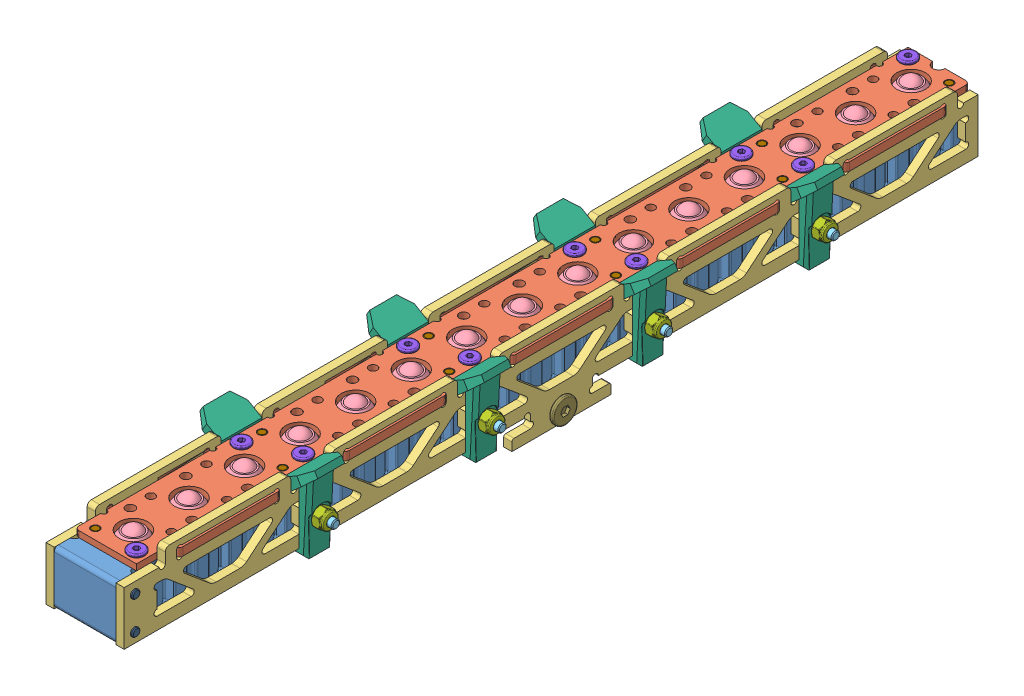
SolidWorks assembly 滚珠轨道装配, configuration 滚珠轨道装配（上）. Lengths in mm.
Overall size (31 24.46 207.5).
78 component instances, 12 part files, 43 mates.
Components (placement in the parent):
- 滚珠轨道嵌块-1: 滚珠轨道嵌块 [默认] x (1 0 0) z (0 -1 0) size (15 207.5 13)
- 滚珠轨道下定位板_1.5mm-1: 滚珠轨道下定位板_1.5mm [默认] at (0 7.25 -94.5) x (1 0 0) z (0 0 -1) size (20 2 202.5)
- 滚珠轨道侧抗弯板_2mm-1: 滚珠轨道侧抗弯板_2mm [滚珠轨道侧抗弯板（上）_2mm] at (-8.5 0 2.5) x (-1 0 0) z (0 0 1) size (2 22 207.5)
- 滚珠轨道侧抗弯板_2mm-2: 滚珠轨道侧抗弯板_2mm [滚珠轨道侧抗弯板（上）_2mm] at (8.5 0 2.5) x (-1 0 0) z (0 0 1) size (2 22 207.5)
- M8×14-1: M8×14 [默认] at (0 2.2286 -94.5) x (0.146553 0 -0.989203) z (-0.989203 0 -0.146553) size (7.99 14.53 7.84)
- M2×8扁头螺丝-1: M2×8扁头螺丝 [默认] at (7.1 0 -60.75) x (0 0 1) z (-1 0 0) size (4 4 8.8)
- 滚珠滑道装饰块-1: 滚珠滑道装饰块 [默认] at (7.5 0 -60.75) x (0 0 -1) z (1 0 0) size (10 20.5 6.81)
- M2防松-1: M2防松 [默认] at (12.5 0 -60.75) x (0 -1 0) z (0 0 1) size (4.56 2.8 4.1)
- M8×14-2: M8×14 [默认] at (0 2.2286 -81) x (0.146553 0 -0.989203) z (-0.989203 0 -0.146553) size (7.99 14.53 7.84)
- M8×14-3: M8×14 [默认] at (0 2.2286 -67.5) x (0.146553 0 -0.989203) z (-0.989203 0 -0.146553) size (7.99 14.53 7.84)
- M8×14-4: M8×14 [默认] at (0 2.2286 -54) x (0.146553 0 -0.989203) z (-0.989203 0 -0.146553) size (7.99 14.53 7.84)
- M8×14-5: M8×14 [默认] at (0 2.2286 -40.5) x (0.146553 0 -0.989203) z (-0.989203 0 -0.146553) size (7.99 14.53 7.84)
- M8×14-6: M8×14 [默认] at (0 2.2286 -27) x (0.146553 0 -0.989203) z (-0.989203 0 -0.146553) size (7.99 14.53 7.84)
- M8×14-7: M8×14 [默认] at (0 2.2286 -13.5) x (0.146553 0 -0.989203) z (-0.989203 0 -0.146553) size (7.99 14.53 7.84)
- M8×14-8: M8×14 [默认] at (0 2.2286 0) x (0.146553 0 -0.989203) z (-0.989203 0 -0.146553) size (7.99 14.53 7.84)
- M8×14-9: M8×14 [默认] at (0 2.2286 13.5) x (0.146553 0 -0.989203) z (-0.989203 0 -0.146553) size (7.99 14.53 7.84)
- M8×14-10: M8×14 [默认] at (0 2.2286 27) x (0.146553 0 -0.989203) z (-0.989203 0 -0.146553) size (7.99 14.53 7.84)
- M8×14-11: M8×14 [默认] at (0 2.2286 40.5) x (0.146553 0 -0.989203) z (-0.989203 0 -0.146553) size (7.99 14.53 7.84)
- M8×14-12: M8×14 [默认] at (0 2.2286 54) x (0.146553 0 -0.989203) z (-0.989203 0 -0.146553) size (7.99 14.53 7.84)
- M8×14-13: M8×14 [默认] at (0 2.2286 67.5) x (0.146553 0 -0.989203) z (-0.989203 0 -0.146553) size (7.99 14.53 7.84)
- M8×14-14: M8×14 [默认] at (0 2.2286 81) x (0.146553 0 -0.989203) z (-0.989203 0 -0.146553) size (7.99 14.53 7.84)
- M8×14-15: M8×14 [默认] at (0 2.2286 94.5) x (0.146553 0 -0.989203) z (-0.989203 0 -0.146553) size (7.99 14.53 7.84)
- M2×8扁头螺丝-2: M2×8扁头螺丝 [默认] at (7.1 0 -20.25) x (0 0 1) z (-1 0 0) size (4 4 8.8)
- M2×8扁头螺丝-3: M2×8扁头螺丝 [默认] at (7.1 0 20.25) x (0 0 1) z (-1 0 0) size (4 4 8.8)
- M2×8扁头螺丝-4: M2×8扁头螺丝 [默认] at (7.1 0 60.75) x (0 0 1) z (-1 0 0) size (4 4 8.8)
- M2防松-2: M2防松 [默认] at (12.5 0 -20.25) x (0 -1 0) z (0 0 1) size (4.56 2.8 4.1)
- M2防松-3: M2防松 [默认] at (12.5 0 20.25) x (0 -1 0) z (0 0 1) size (4.56 2.8 4.1)
- M2防松-4: M2防松 [默认] at (12.5 0 60.75) x (0 -1 0) z (0 0 1) size (4.56 2.8 4.1)
- 滚珠滑道装饰块-2: 滚珠滑道装饰块 [默认] at (7.5 0 -20.25) x (0 0 -1) z (1 0 0) size (10 20.5 6.81)
- 滚珠滑道装饰块-3: 滚珠滑道装饰块 [默认] at (7.5 0 20.25) x (0 0 -1) z (1 0 0) size (10 20.5 6.81)
- 滚珠滑道装饰块-4: 滚珠滑道装饰块 [默认] at (7.5 0 60.75) x (0 0 -1) z (1 0 0) size (10 20.5 6.81)
- M2×8扁头螺丝-5: M2×8扁头螺丝 [默认] at (-7.1 0 -60.75) x (0 0 -1) z (1 0 0) size (4 4 8.8)
- M2防松-5: M2防松 [默认] at (-12.5 0 -60.75) x (0 -1 0) z (0 0 -1) size (4.56 2.8 4.1)
- 滚珠滑道装饰块-5: 滚珠滑道装饰块 [默认] at (-7.5 0 -60.75) x (0 0 1) z (-1 0 0) size (10 20.5 6.81)
- M2×8扁头螺丝-6: M2×8扁头螺丝 [默认] at (-7.1 0 -20.25) x (0 0 -1) z (1 0 0) size (4 4 8.8)
- M2×8扁头螺丝-7: M2×8扁头螺丝 [默认] at (-7.1 0 20.25) x (0 0 -1) z (1 0 0) size (4 4 8.8)
- M2×8扁头螺丝-8: M2×8扁头螺丝 [默认] at (-7.1 0 60.75) x (0 0 -1) z (1 0 0) size (4 4 8.8)
- M2防松-6: M2防松 [默认] at (-12.5 0 -20.25) x (0 -1 0) z (0 0 -1) size (4.56 2.8 4.1)
- M2防松-7: M2防松 [默认] at (-12.5 0 20.25) x (0 -1 0) z (0 0 -1) size (4.56 2.8 4.1)
- M2防松-8: M2防松 [默认] at (-12.5 0 60.75) x (0 -1 0) z (0 0 -1) size (4.56 2.8 4.1)
- 滚珠滑道装饰块-6: 滚珠滑道装饰块 [默认] at (-7.5 0 -20.25) x (0 0 1) z (-1 0 0) size (10 20.5 6.81)
- 滚珠滑道装饰块-7: 滚珠滑道装饰块 [默认] at (-7.5 0 20.25) x (0 0 1) z (-1 0 0) size (10 20.5 6.81)
- 滚珠滑道装饰块-8: 滚珠滑道装饰块 [默认] at (-7.5 0 60.75) x (0 0 1) z (-1 0 0) size (10 20.5 6.81)
- M2×18扁头螺丝-1: M2×18扁头螺丝 [默认] at (5 8.4 98.75) x (0.972997 0 0.230819) z (0 1 0) size (4 4 18.8)
- M2×15销钉-1: M2×15销钉 [默认] at (-5 0.5 98.75) x (0.836525 0 -0.547929) z (0 -1 0) size (2 2 15)
- M2防松-9: M2防松 [默认] at (5 -7.5 98.75) x (0.590021 0 0.807388) z (0.807388 0 -0.590021) size (4.56 2.8 4.1)
- M2×18扁头螺丝-2: M2×18扁头螺丝 [默认] at (-5 8.4 63.25) x (1 0 0) z (0 1 0) size (4 4 18.8)
- M2×15销钉-2: M2×15销钉 [默认] at (5 0.5 63.25) x (0.243249 0 -0.969964) z (0 1 0) size (2 2 15)
- M2防松-10: M2防松 [默认] at (-5 -7.5 63.25) x (-0.991968 0 0.126492) z (0.126492 0 0.991968) size (4.56 2.8 4.1)
- M2防松-11: M2防松 [默认] at (5 -7.5 58.25) x (0.590021 0 0.807388) z (0.807388 0 -0.590021) size (4.56 2.8 4.1)
- M2防松-12: M2防松 [默认] at (5 -7.5 17.75) x (0.590021 0 0.807388) z (0.807388 0 -0.590021) size (4.56 2.8 4.1)
- M2防松-13: M2防松 [默认] at (5 -7.5 -22.75) x (0.590021 0 0.807388) z (0.807388 0 -0.590021) size (4.56 2.8 4.1)
- M2防松-14: M2防松 [默认] at (5 -7.5 -63.25) x (0.590021 0 0.807388) z (0.807388 0 -0.590021) size (4.56 2.8 4.1)
- M2×18扁头螺丝-3: M2×18扁头螺丝 [默认] at (5 8.4 58.25) x (0.972997 0 0.230819) z (0 1 0) size (4 4 18.8)
- M2×18扁头螺丝-4: M2×18扁头螺丝 [默认] at (5 8.4 17.75) x (0.972997 0 0.230819) z (0 1 0) size (4 4 18.8)
- M2×18扁头螺丝-5: M2×18扁头螺丝 [默认] at (5 8.4 -22.75) x (0.972997 0 0.230819) z (0 1 0) size (4 4 18.8)
- M2×18扁头螺丝-6: M2×18扁头螺丝 [默认] at (5 8.4 -63.25) x (0.972997 0 0.230819) z (0 1 0) size (4 4 18.8)
- M2×15销钉-3: M2×15销钉 [默认] at (-5 0.5 58.25) x (0.836525 0 -0.547929) z (0 -1 0) size (2 2 15)
- M2×15销钉-4: M2×15销钉 [默认] at (-5 0.5 17.75) x (0.836525 0 -0.547929) z (0 -1 0) size (2 2 15)
- M2×15销钉-5: M2×15销钉 [默认] at (-5 0.5 -22.75) x (0.836525 0 -0.547929) z (0 -1 0) size (2 2 15)
- M2×15销钉-6: M2×15销钉 [默认] at (-5 0.5 -63.25) x (0.836525 0 -0.547929) z (0 -1 0) size (2 2 15)
- M2×15销钉-7: M2×15销钉 [默认] at (5 0.5 22.75) x (0.243249 0 -0.969964) z (0 1 0) size (2 2 15)
- M2×15销钉-8: M2×15销钉 [默认] at (5 0.5 -17.75) x (0.243249 0 -0.969964) z (0 1 0) size (2 2 15)
- M2×15销钉-9: M2×15销钉 [默认] at (5 0.5 -58.25) x (0.243249 0 -0.969964) z (0 1 0) size (2 2 15)
- M2×15销钉-10: M2×15销钉 [默认] at (5 0.5 -98.75) x (0.243249 0 -0.969964) z (0 1 0) size (2 2 15)
- M2防松-15: M2防松 [默认] at (-5 -7.5 22.75) x (-0.991968 0 0.126492) z (0.126492 0 0.991968) size (4.56 2.8 4.1)
- M2防松-16: M2防松 [默认] at (-5 -7.5 -17.75) x (-0.991968 0 0.126492) z (0.126492 0 0.991968) size (4.56 2.8 4.1)
- M2防松-17: M2防松 [默认] at (-5 -7.5 -58.25) x (-0.991968 0 0.126492) z (0.126492 0 0.991968) size (4.56 2.8 4.1)
- M2防松-18: M2防松 [默认] at (-5 -7.5 -98.75) x (-0.991968 0 0.126492) z (0.126492 0 0.991968) size (4.56 2.8 4.1)
- M2×18扁头螺丝-7: M2×18扁头螺丝 [默认] at (-5 8.4 22.75) x (1 0 0) z (0 1 0) size (4 4 18.8)
- M2×18扁头螺丝-8: M2×18扁头螺丝 [默认] at (-5 8.4 -17.75) x (1 0 0) z (0 1 0) size (4 4 18.8)
- M2×18扁头螺丝-9: M2×18扁头螺丝 [默认] at (-5 8.4 -58.25) x (1 0 0) z (0 1 0) size (4 4 18.8)
- M2×18扁头螺丝-10: M2×18扁头螺丝 [默认] at (-5 8.4 -98.75) x (1 0 0) z (0 1 0) size (4 4 18.8)
- M2×20销钉-1: M2×20销钉 [默认] at (0 -4 103.75) x (0 -0.999299 0.037438) z (1 0 0) size (2 2 20)
- M2×20销钉-2: M2×20销钉 [默认] at (0 4 103.75) x (0 -0.806996 -0.590557) z (1 0 0) size (2 2 20)
- M3×Φ5×15-1: M3×Φ5×15 [默认] at (0 -9 0) x (0 0.550608 -0.834764) z (1 0 0) size (5 5 15)
- M3×6扁头螺丝-1: M3×6扁头螺丝 [默认] at (10 -9 0) x (0 0 -1) z (1 0 0) size (6 6 7)
- M3×6扁头螺丝-2: M3×6扁头螺丝 [默认] at (-10 -9 0) x (0 0 1) z (-1 0 0) size (6 6 7)
Mates (geometry in assembly coordinates):
- 重合1: coincident anti-aligned: plane of 滚珠轨道嵌块-1 through (0 0 0) normal (0 -1 0)
- 重合2: coincident aligned: plane of 滚珠轨道嵌块-1 through (0 0 0) normal (1 0 0)
- 重合3: coincident aligned: plane of 滚珠轨道嵌块-1 through (0 0 0) normal (0 0 1)
- 同心1: concentric aligned: cylinder of 滚珠轨道嵌块-1 through (-7.5 -4 103.75) axis (1 0 0) radius 1.025; cylinder of 滚珠轨道侧抗弯板_2mm-2 through (7.5 -4 103.75) axis (1 0 0) radius 1
- 同心2: concentric aligned: cylinder of 滚珠轨道嵌块-1 through (-7.5 4 103.75) axis (1 0 0) radius 1.025; cylinder of 滚珠轨道侧抗弯板_2mm-2 through (7.5 4 103.75) axis (1 0 0) radius 1
- 同心3: concentric aligned: cylinder of 滚珠轨道嵌块-1 through (-7.5 -4 103.75) axis (1 0 0) radius 1.025; cylinder of 滚珠轨道侧抗弯板_2mm-1 through (-9.5 -4 103.75) axis (1 0 0) radius 1
- 同心4: concentric aligned: cylinder of 滚珠轨道嵌块-1 through (-7.5 4 103.75) axis (1 0 0) radius 1.025; cylinder of 滚珠轨道侧抗弯板_2mm-1 through (-9.5 4 103.75) axis (1 0 0) radius 1
- 重合4: coincident anti-aligned: plane of 滚珠轨道嵌块-1 through (-7.5 -6.5 101.25) normal (-1 0 0); plane of 滚珠轨道侧抗弯板_2mm-1 through (-7.5 0 2.5) normal (1 0 0)
- 重合5: coincident anti-aligned: plane of 滚珠轨道嵌块-1 through (7.5 -6.5 101.25) normal (1 0 0); plane of 滚珠轨道侧抗弯板_2mm-2 through (7.5 0 2.5) normal (-1 0 0)
- 同心5: concentric aligned: cylinder of 滚珠轨道嵌块-1 through (5 6.5 -98.75) axis (0 -1 0) radius 0.975; cylinder of 滚珠轨道下定位板_2mm-1 through (5 8 -98.75) axis (0 -1 0) radius 1
- 同心6: concentric aligned: cylinder of 滚珠轨道嵌块-1 through (-5 6.5 98.75) axis (0 -1 0) radius 0.975; cylinder of 滚珠轨道下定位板_2mm-1 through (-5 8 98.75) axis (0 -1 0) radius 1
- 重合6: coincident anti-aligned: plane of 滚珠轨道嵌块-1 through (0 6.5 0) normal (0 1 0); plane of 滚珠轨道下定位板_2mm-1 through (0 6.5 -94.5) normal (0 -1 0)
- 同心7: concentric anti-aligned: cylinder of 滚珠轨道嵌块-1 through (0 -6.5 -94.5) axis (0 1 0) radius 3.45; cylinder of M8×14-1 through (0 -4.7714 -94.5) axis (0 -1 0) radius 3.9
- 重合7: coincident anti-aligned: circle of 滚珠轨道下定位板_2mm-1; cone of M8×14-1 through (0 5.4286 -94.5) axis (0 1 0)
- 重合8: coincident anti-aligned: plane of 滚珠轨道侧抗弯板_2mm-2 through (7.5 0 2.5) normal (-1 0 0); plane of M2×8扁头螺丝-1 through (7.5 0 -60.75) normal (1 0 0)
- 同心8: concentric aligned: cylinder of 滚珠轨道侧抗弯板_2mm-2 through (9.5 0 -60.75) axis (-1 0 0) radius 1.05; cylinder of M2×8扁头螺丝-1 through (15.5 0 -60.75) axis (-1 0 0) radius 1
- 重合9: coincident anti-aligned: plane of 滚珠轨道侧抗弯板_2mm-2 through (9.5 0 2.5) normal (1 0 0); plane of 滚珠滑道装饰块-1 through (9.5 6.5 -57.75) normal (-1 0 0)
- 同心9: concentric aligned: cylinder of M2×8扁头螺丝-1 through (15.5 0 -60.75) axis (-1 0 0) radius 1; cylinder of 滚珠滑道装饰块-1 through (11.5 0 -60.75) axis (-1 0 0) radius 1.1
- 平行1: parallel anti-aligned: plane of 滚珠轨道侧抗弯板_2mm-2 through (7.5 -6.5 -101.25) normal (0 -1 0); plane of 滚珠滑道装饰块-1 through (9.5 -6.5 -57.75) normal (0 1 0)
- 同心10: concentric anti-aligned: cylinder of M2×8扁头螺丝-1 through (15.5 0 -60.75) axis (-1 0 0) radius 1; cylinder of M2防松-1 through (13.5 0 -60.75) axis (1 0 0) radius 1
- 重合10: coincident anti-aligned: plane of 滚珠滑道装饰块-1 through (11.5 0 -60.75) normal (1 0 0); plane of M2防松-1 through (11.5 0 -60.75) normal (-1 0 0)
- 同心11: concentric anti-aligned: cylinder of 滚珠轨道嵌块-1 through (5 6.5 98.75) axis (0 -1 0) radius 1.1; cylinder of M2×18扁头螺丝-1 through (5 -10 98.75) axis (0 1 0) radius 1
- 重合11: coincident anti-aligned: plane of 滚珠轨道下定位板_2mm-1 through (0 8 -94.5) normal (0 1 0); plane of M2×18扁头螺丝-1 through (5 8 98.75) normal (0 -1 0)
- 同心12: concentric anti-aligned: cylinder of 滚珠轨道嵌块-1 through (-5 6.5 98.75) axis (0 -1 0) radius 0.975; cylinder of M2×15销钉-1 through (-5 -7 98.75) axis (0 1 0) radius 1
- 重合12: coincident aligned: plane of 滚珠轨道下定位板_2mm-1 through (0 8 -94.5) normal (0 1 0); plane of M2×15销钉-1 through (-5 8 98.75) normal (0 1 0)
- 同心13: concentric anti-aligned: cylinder of M2×18扁头螺丝-1 through (5 -10 98.75) axis (0 1 0) radius 1; cylinder of M2防松-9 through (5 -8.5 98.75) axis (0 -1 0) radius 1
- 重合13: coincident anti-aligned: plane of 滚珠轨道嵌块-1 through (0 -6.5 0) normal (0 -1 0); plane of M2防松-9 through (5 -6.5 98.75) normal (0 1 0)
- 同心14: concentric anti-aligned: cylinder of 滚珠轨道嵌块-1 through (-5 6.5 63.25) axis (0 -1 0) radius 1.1; cylinder of M2×18扁头螺丝-2 through (-5 -10 63.25) axis (0 1 0) radius 1
- 重合14: coincident anti-aligned: plane of 滚珠轨道下定位板_2mm-1 through (0 8 -94.5) normal (0 1 0); plane of M2×18扁头螺丝-2 through (-5 8 63.25) normal (0 -1 0)
- 同心15: concentric anti-aligned: cylinder of M2×18扁头螺丝-2 through (-5 -10 63.25) axis (0 1 0) radius 1; cylinder of M2防松-10 through (-5 -8.5 63.25) axis (0 -1 0) radius 1
- 重合15: coincident anti-aligned: plane of 滚珠轨道嵌块-1 through (0 -6.5 0) normal (0 -1 0); plane of M2防松-10 through (-5 -6.5 63.25) normal (0 1 0)
- 同心16: concentric aligned: cylinder of 滚珠轨道嵌块-1 through (5 6.5 63.25) axis (0 -1 0) radius 0.975; cylinder of M2×15销钉-2 through (5 8 63.25) axis (0 -1 0) radius 1
- 重合16: coincident aligned: plane of 滚珠轨道下定位板_2mm-1 through (0 8 -94.5) normal (0 1 0); plane of M2×15销钉-2 through (5 8 63.25) normal (0 1 0)
- 同心17: concentric anti-aligned: cylinder of 滚珠轨道嵌块-1 through (-7.5 -4 103.75) axis (1 0 0) radius 1.025; cylinder of M2×20销钉-1 through (10 -4 103.75) axis (-1 0 0) radius 1
- 重合17: coincident aligned: plane of M2×20销钉-1 through (0 -4 103.75) normal (1 0 0)
- 同心18: concentric anti-aligned: cylinder of 滚珠轨道嵌块-1 through (-7.5 4 103.75) axis (1 0 0) radius 1.025; cylinder of M2×20销钉-2 through (10 4 103.75) axis (-1 0 0) radius 1
- 重合18: coincident aligned: plane of M2×20销钉-1 through (10 -4 103.75) normal (1 0 0); plane of M2×20销钉-2 through (10 4 103.75) normal (1 0 0)
- 同心19: concentric anti-aligned: cylinder of 滚珠轨道侧抗弯板_2mm-1 through (-9.5 -9 0) axis (1 0 0) radius 1.55; cylinder of M3×Φ5×15-1 through (7.5 -9 0) axis (-1 0 0) radius 1.5
- 重合19: coincident anti-aligned: plane of 滚珠轨道侧抗弯板_2mm-2 through (7.5 0 2.5) normal (-1 0 0); plane of M3×Φ5×15-1 through (7.5 -9 0) normal (1 0 0)
- 同心20: concentric anti-aligned: cylinder of M3×Φ5×15-1 through (7.5 -9 0) axis (-1 0 0) radius 1.5; cylinder of M3×6扁头螺丝-1 through (3.5 -9 0) axis (1 0 0) radius 1.5
- 重合20: coincident anti-aligned: plane of 滚珠轨道侧抗弯板_2mm-2 through (9.5 0 2.5) normal (1 0 0); plane of M3×6扁头螺丝-1 through (9.5 -9 0) normal (-1 0 0)
- 同心21: concentric anti-aligned: cylinder of 滚珠轨道侧抗弯板_2mm-1 through (-9.5 -9 0) axis (1 0 0) radius 1.55; cylinder of M3×6扁头螺丝-2 through (-3.5 -9 0) axis (-1 0 0) radius 1.5
- 重合21: coincident anti-aligned: plane of 滚珠轨道侧抗弯板_2mm-1 through (-9.5 0 2.5) normal (-1 0 0); plane of M3×6扁头螺丝-2 through (-9.5 -9 0) normal (1 0 0)
